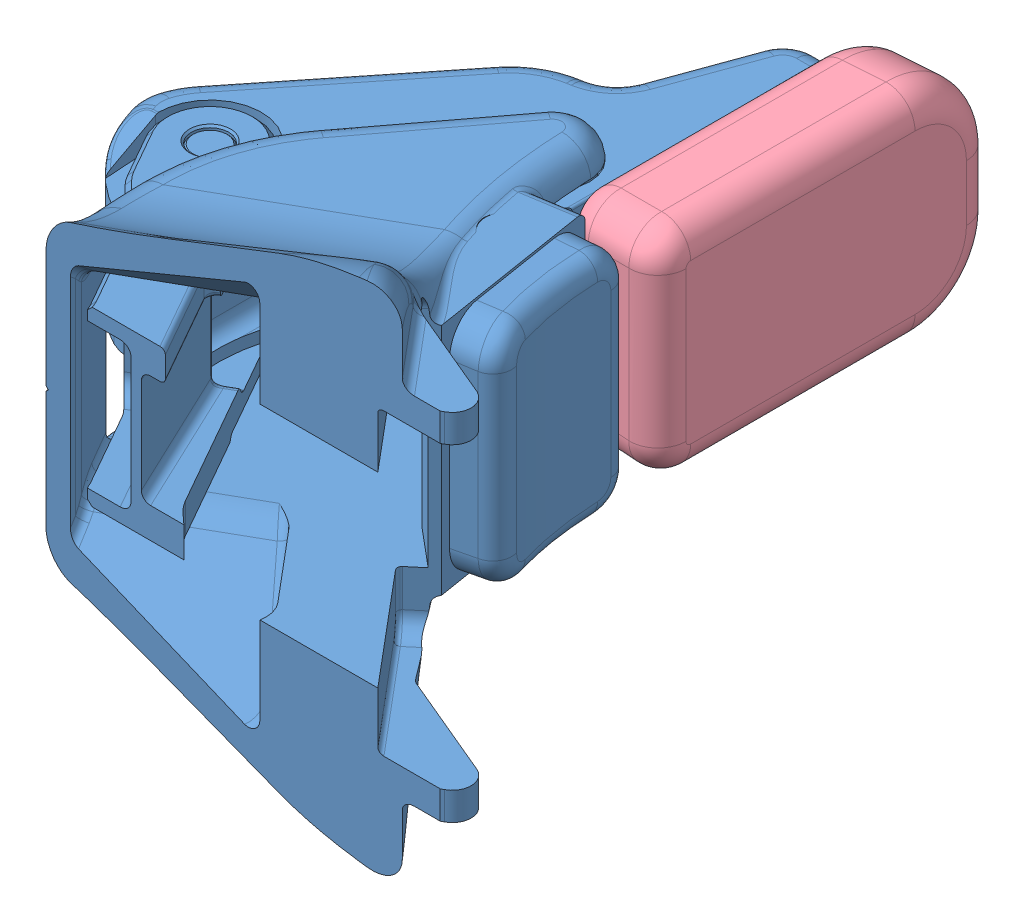
SolidWorks assembly PR2_MODULARITY_GRPR_ASM, configuration Default. Lengths in mm.
Overall size (56.54 55.12 73.97).
7 component instances, 4 part files, 0 mates.
Components (placement in the parent):
- PR2_MODULARITY_GRPR-1: PR2_MODULARITY_GRPR [Default] at origin size (56.54 55.12 67.62)
- SCR_SHCS_M3_050_8_SST_A2-70-1: SCR_SHCS_M3_050_8_SST_A2-70 [Default] at (-52.9929 5.75 -94.313) x (-1 0 0) z (0 1 0) size (11 5.5 5.5)
- SCR_SHCS_M3_050_8_SST_A2-70-2: SCR_SHCS_M3_050_8_SST_A2-70 [Default] at (-52.9929 5.75 -94.313) x (-1 0 0) z (0 1 0) size (11 5.5 5.5)
- SCR_SHCS_M3_050_8_SST_A2-70-3: SCR_SHCS_M3_050_8_SST_A2-70 [Default] at (-52.9929 -4.25 -94.313) x (-1 0 0) z (0 1 0) size (11 5.5 5.5)
- SCR_SHCS_M3_050_8_SST_A2-70-4: SCR_SHCS_M3_050_8_SST_A2-70 [Default] at (-52.9929 -4.25 -94.313) x (-1 0 0) z (0 1 0) size (11 5.5 5.5)
- PR2_HAND_FINGER_CORE-1: PR2_HAND_FINGER_CORE [Default] at (-47.7429 0.75 -76.813) x (0 0 -1) z (0 -1 0) size (32 8.5 19)
- PR2_HAND_FINGER_RUBBER-1: PR2_HAND_FINGER_RUBBER [Default] at (-50.1429 0.75 -74.813) x (0 0 -1) z (0 -1 0) size (36.2 11.55 23.2)
